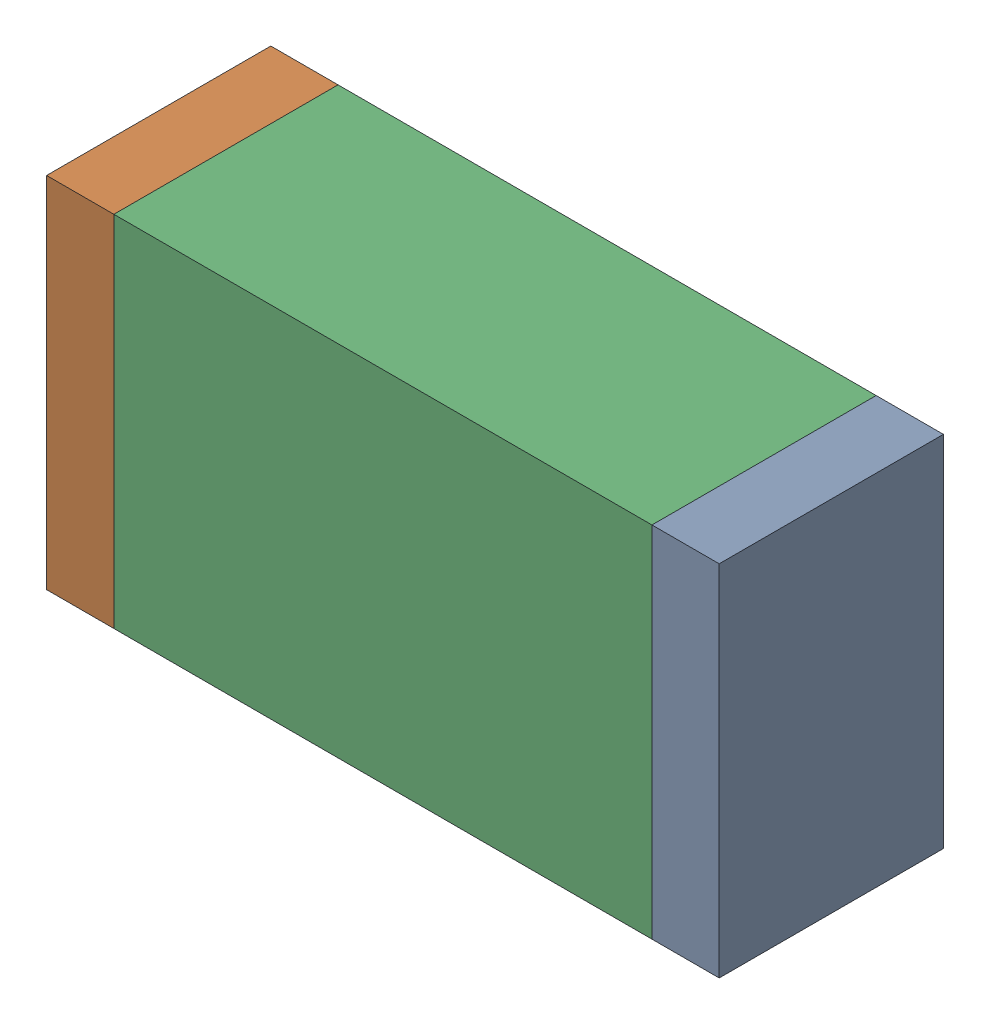
SolidWorks assembly D4, configuration Default. Lengths in mm.
Overall size (1.5 0.8 0.5).
6 component instances, 2 part files, 0 mates.
Components (placement in the parent):
- 836752496-1: 836752496 [Default] at (127.725 12.1 0) size (0.15 0.8 0.5)
  - Extruded_2-1: Extruded_2 [Default] at origin size (0.15 0.8 0.5)
- 836752496-2: 836752496 [Default] at (126.375 12.1 0) size (0.15 0.8 0.5)
  - Extruded_2-1: Extruded_2 [Default] at origin size (0.15 0.8 0.5)
- 836752368-1: 836752368 [Default] at (127.05 12.1 0) size (1.2 0.8 0.5)
  - Extruded-1: Extruded [Default] at origin size (1.2 0.8 0.5)
